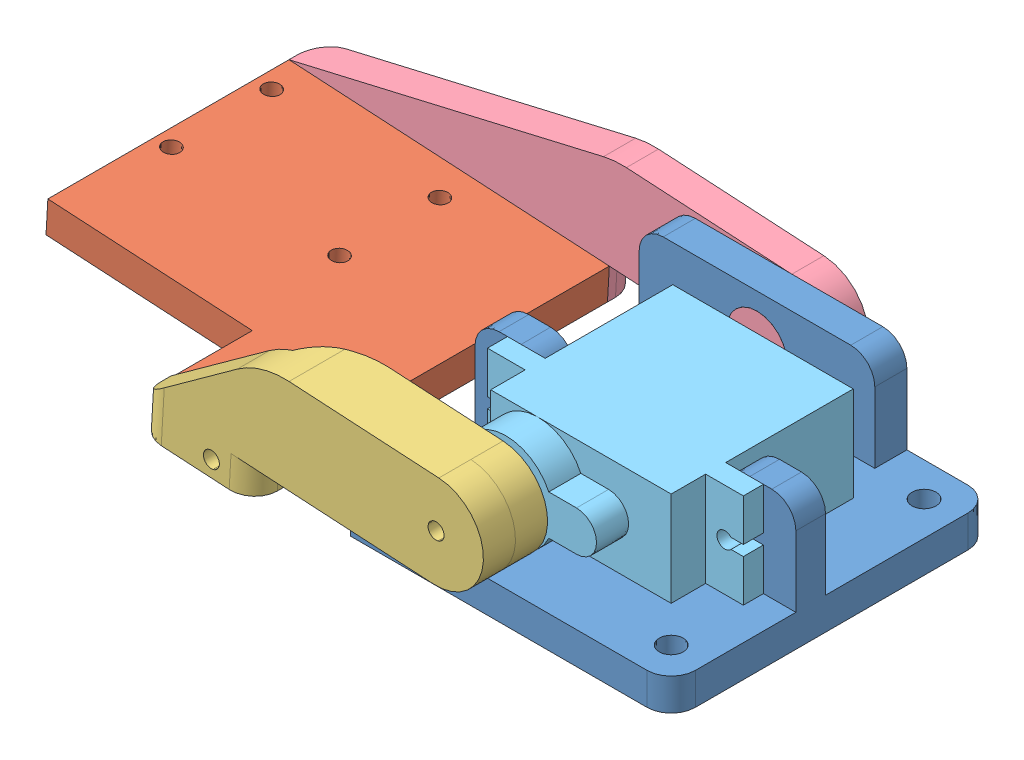
SolidWorks assembly Camera TilT ASSEMBLY, configuration Default. Lengths in mm.
Overall size (87.94 19.71 48).
5 component instances, 5 part files, 10 mates.
Components (placement in the parent):
- TI-1: TI [Default] at (12.4367 -3.7568 -9.3775) size (40 15.8 40)
- TI.2SLDPRT-1: TI.2SLDPRT [Default] at (-35.4762 -1.3009 -9.3775) x (0.99832 -0.057939 0) z (0 0 1) size (40 5 40)
- TI3-1: TI3 [Default] at (-35.3603 0.6957 10.6225) x (0.99832 -0.057939 0) z (-0.057939 -0.99832 0) size (42.64 8 15.8)
- TI4-1: TI4 [Default] at (-35.3603 0.6957 -33.3775) x (0.99832 -0.057939 0) z (-0.057939 -0.99832 0) size (68 8 15.8)
- Servo-1: Servo [Default] at (12.4418 6.1432 -9.4658) x (1 0 0) z (0 -1 0) size (31.9 29.9 11.8)
Mates (geometry in assembly coordinates):
- Concentric12: concentric anti-aligned: circle of TI-1; circle of TI4-1
- Coincident2: coincident aligned: plane of TI-1 through (21.8167 12.0432 -25.3775) normal (0 0 1); plane of TI4-1 through (7.1267 6.1432 -25.3775) normal (0 0 1)
- Concentric13: concentric aligned: circle of TI.2SLDPRT-1; circle of TI4-1
- Concentric14: concentric aligned: circle of TI.2SLDPRT-1; circle of TI4-1
- Coincident5: coincident anti-aligned: plane of TI.2SLDPRT-1 through (-55.2108 3.8511 -29.3775) normal (0 0 -1); plane of TI4-1 through (7.1267 6.1432 -29.3775) normal (0 0 1)
- Concentric15: concentric anti-aligned: circle of TI.2SLDPRT-1; circle of TI3-1
- Coincident7: coincident anti-aligned: plane of TI.2SLDPRT-1 through (-55.2108 3.8511 10.6225) normal (0 0 1); plane of TI3-1 through (7.1267 6.1429 10.6225) normal (0 0 -1)
- Parallel3: parallel aligned: line of TI.2SLDPRT-1 through (-29.7299 2.3723 10.6225) axis (-0.057939 -0.99832 0); line of TI3-1 through (-29.8957 2.3814 10.6225) axis (-0.057939 -0.99832 0)
- Concentric16: concentric anti-aligned: circle of TI-1; circle of Servo-1
- Coincident11: coincident anti-aligned: plane of TI-1 through (-7.5633 12.0432 -4.9158) normal (0 0 1); plane of Servo-1 through (-1.2082 6.1432 -4.9158) normal (0 0 -1)
